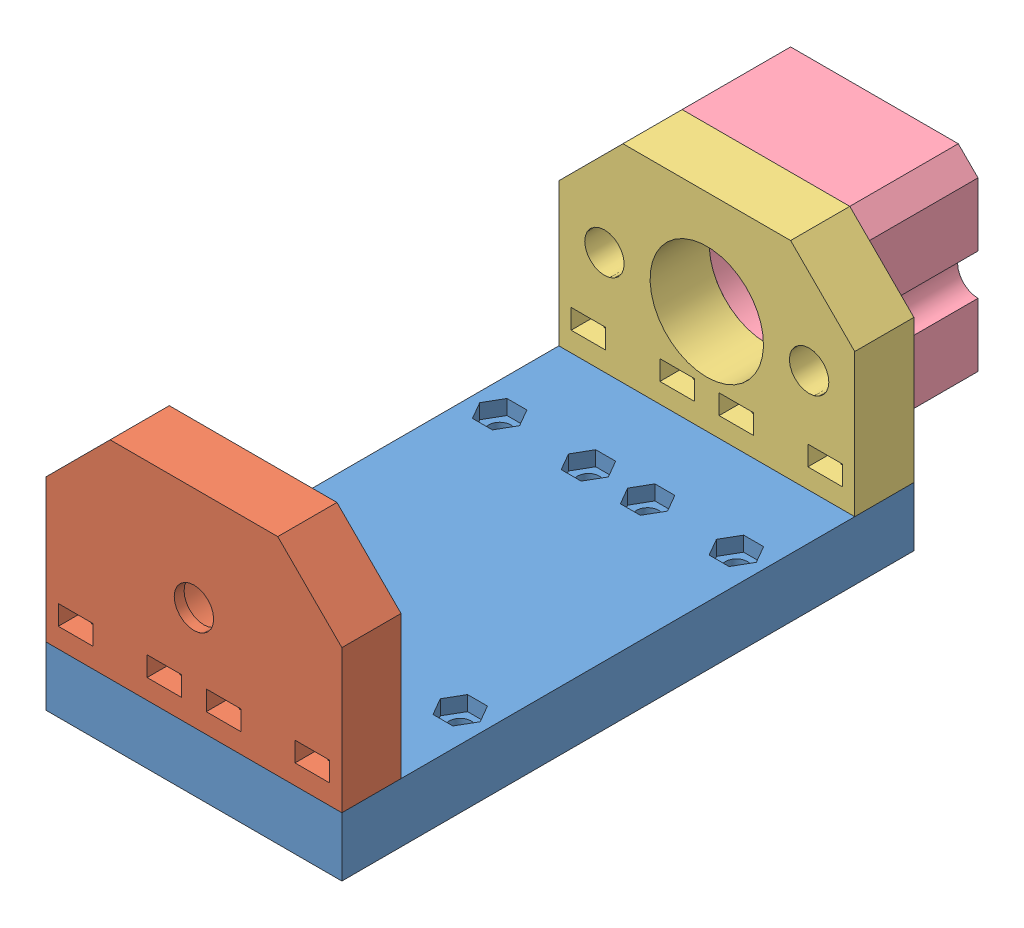
SolidWorks assembly New_carriage, configuration Default. Lengths in mm.
Overall size (60 54 138).
4 component instances, 4 part files, 7 mates.
Components (placement in the parent):
- Carriage_plate-1: Carriage_plate [Default] at origin size (60 12 116)
- Buttom_plate-1: Buttom_plate [Default] at (0 33 58) x (1 0 0) z (0 1 0) size (60 12 42)
- Top_plate-1: Top_plate [Default] at (0 33 -46) x (1 0 0) z (0 1 0) size (60 12 42)
- Stepper_spacer-1: Stepper_spacer [Default] at (0 33 -58) x (1 0 0) z (0 1 0) size (42 22 42)
Mates (geometry in assembly coordinates):
- Concentric1: concentric anti-aligned: circle of Carriage_plate-1; circle of Buttom_plate-1
- Coincident2: coincident anti-aligned: circle of Carriage_plate-1; circle of Buttom_plate-1
- Concentric2: concentric anti-aligned: circle of Carriage_plate-1; circle of Top_plate-1
- Coincident4: coincident anti-aligned: circle of Carriage_plate-1; circle of Top_plate-1
- Coincident5: coincident anti-aligned: plane of Top_plate-1 through (0 33 -58) normal (0 0 -1); plane of Stepper_spacer-1 through (0 33 -58) normal (0 0 1)
- Coincident6: coincident aligned: circle of Top_plate-1; circle of Stepper_spacer-1
- Coincident7: coincident anti-aligned: plane of Carriage_plate-1 through (0 12 0) normal (0 1 0); plane of Stepper_spacer-1 through (-21 12 -80) normal (0 -1 0)
